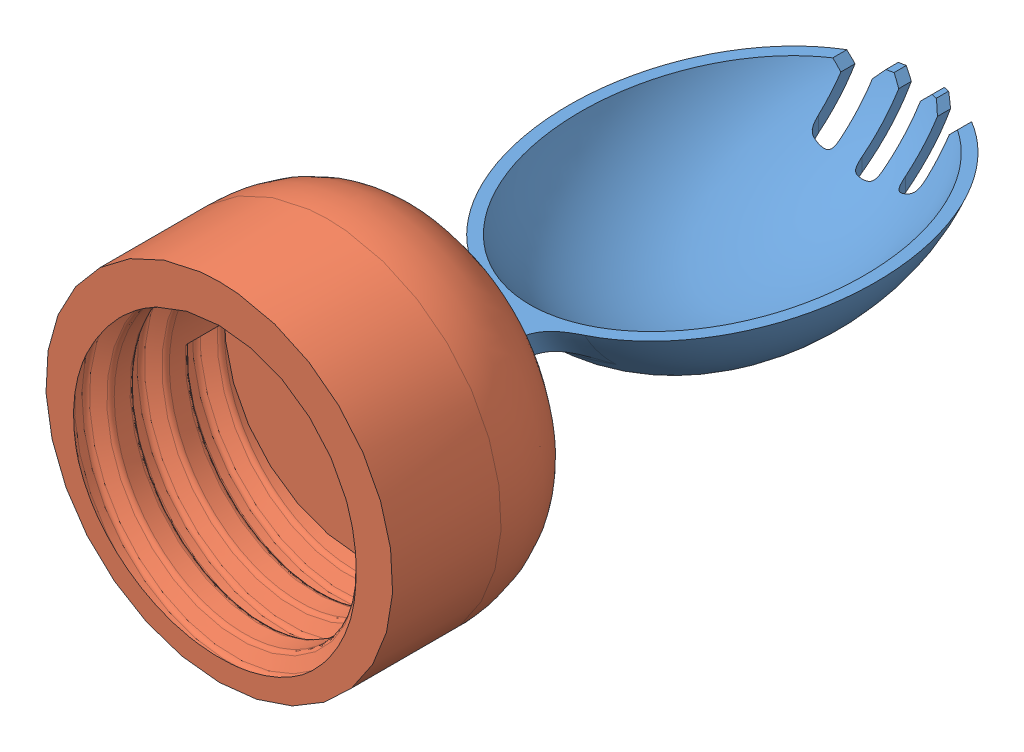
SolidWorks assembly ^Sork head_keinHohlraum, configuration Standard. Lengths in mm.
Overall size (32.71 32.71 65.58).
2 component instances, 2 part files, 1 mates.
Components (placement in the parent):
- Head-1: Head [Standard] at (-22.5326 -24.8818 41.2177) size (29.08 15.9 44.81)
- kappe1-1: kappe1 [Default] at (-22.9097 -30.0981 87.2177) x (1 0 0) z (0 1 0) size (32.71 20.82 32.71)
Mates (geometry in assembly coordinates):
- Deckungsgleich1: coincident anti-aligned: plane of Head-1 through (-22.5326 -31.8818 67.2177) normal (0 0 1); plane of kappe1-1 through (-22.9097 -30.0981 67.2177) normal (0 0 -1)
